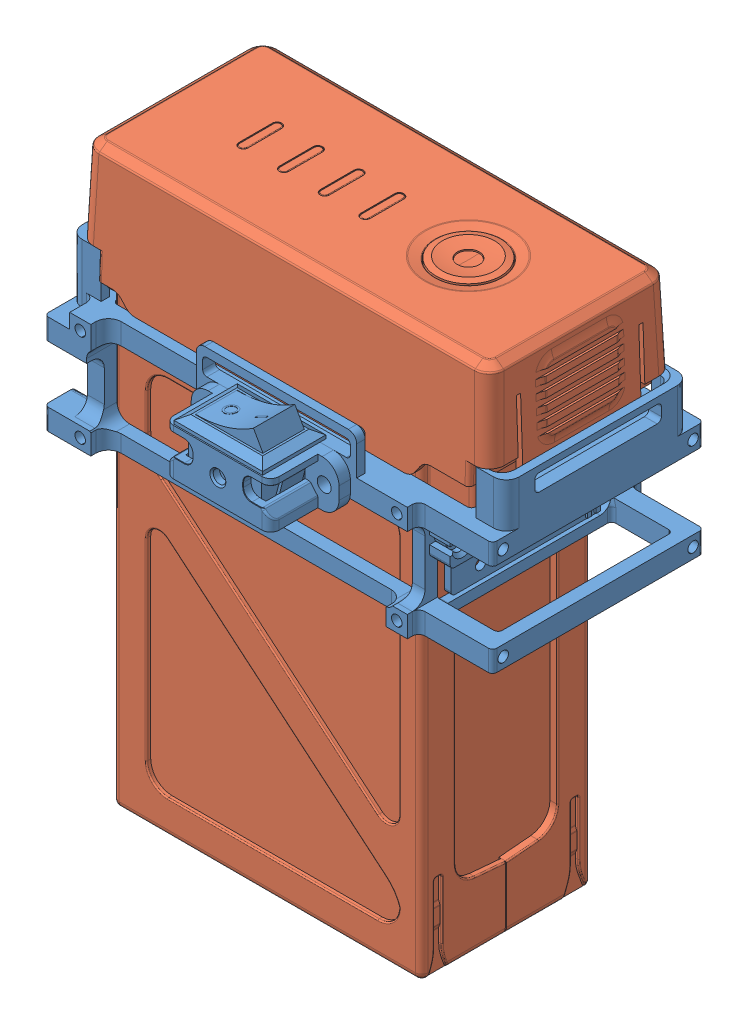
SolidWorks assembly DP_电池装配体1.0, configuration 默认. Lengths in mm.
Overall size (103.5 134.81 69.3).
2 component instances, 2 part files, 3 mates.
Components (placement in the parent):
- DP_RoboMaster 电池架（兼容型）-1: DP_RoboMaster 电池架（兼容型） [Default] at (-57.9391 2.2099 96.5476) size (103.5 37.5 69.3)
- DP_TB47S电池-1: DP_TB47S电池 [默认] at (-59.0391 2.7599 97.3476) size (101.5 134.81 44.3)
Mates (geometry in assembly coordinates):
- 重合1: coincident anti-aligned: plane of DP_RoboMaster 电池架（兼容型）-1 through (38.5621 -27.4913 117.0476) normal (0 0 -1); plane of TB47S电池-1 through (-18.3391 -44.0401 117.0476) normal (0 0 1)
- 重合2: coincident anti-aligned: plane of DP_RoboMaster 电池架（兼容型）-1 through (-54.9391 -27.4913 121.1488) normal (1 0 0); plane of TB47S电池-1 through (-54.9391 -101.0401 96.9476) normal (-1 0 0)
- 重合3: coincident anti-aligned: plane of DP_RoboMaster 电池架（兼容型）-1 through (26.7609 -3.4401 102.4976) normal (0 1 0); plane of TB47S电池-1 through (21.2009 -3.4401 89.9376) normal (0 -1 0)
